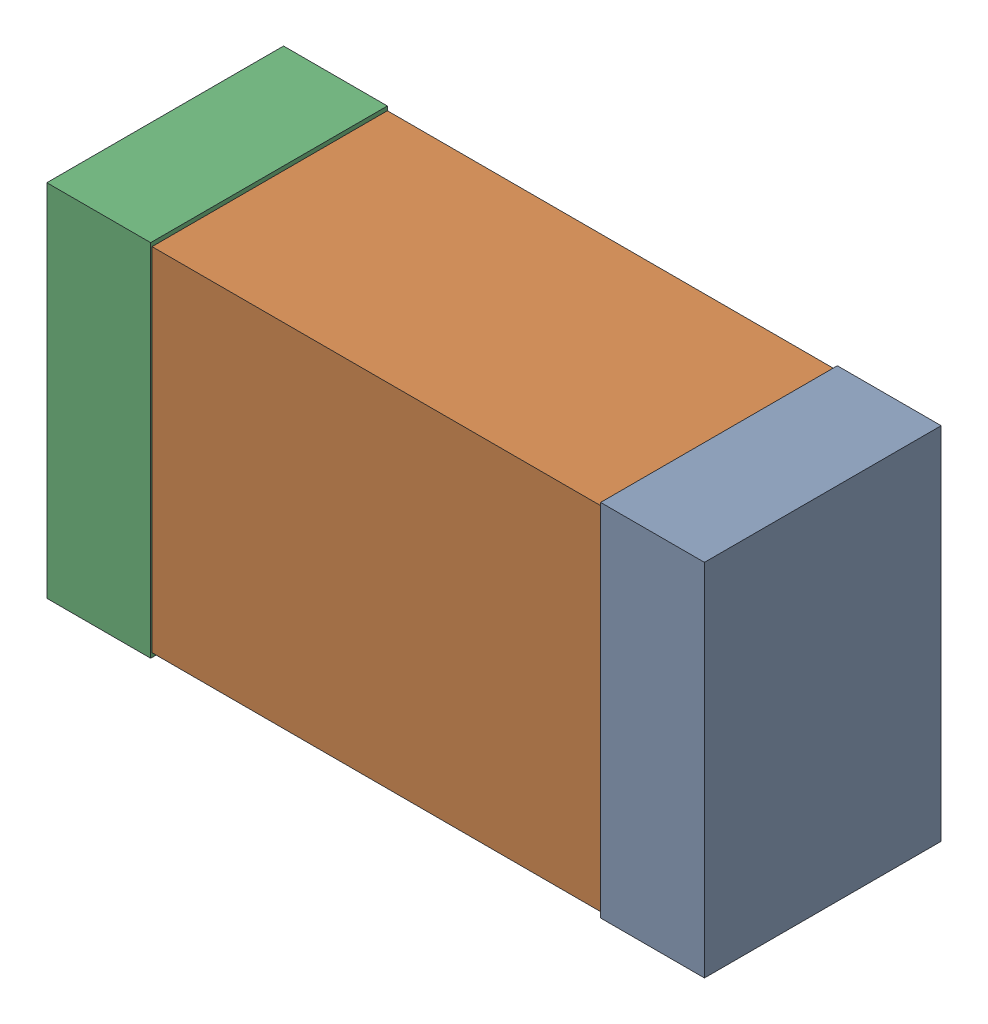
SolidWorks assembly RoNKanaloa_v2.0.0_Power, configuration Default. Lengths in mm.
Overall size (2.38 1.3 0.85).
6 component instances, 2 part files, 0 mates.
Components (placement in the parent):
- 352877648-1: 352877648 [Default] at (41.64 128.016 0) size (0.38 1.3 0.85)
  - Extruded_14-1: Extruded_14 [Default] at origin size (0.38 1.3 0.85)
- 352877904-1: 352877904 [Default] at (40.64 128.016 0) size (2.2 1.27 0.85)
  - Extruded_18-1: Extruded_18 [Default] at origin size (2.2 1.27 0.85)
- 352877648-2: 352877648 [Default] at (39.64 128.016 0) size (0.38 1.3 0.85)
  - Extruded_14-1: Extruded_14 [Default] at origin size (0.38 1.3 0.85)
